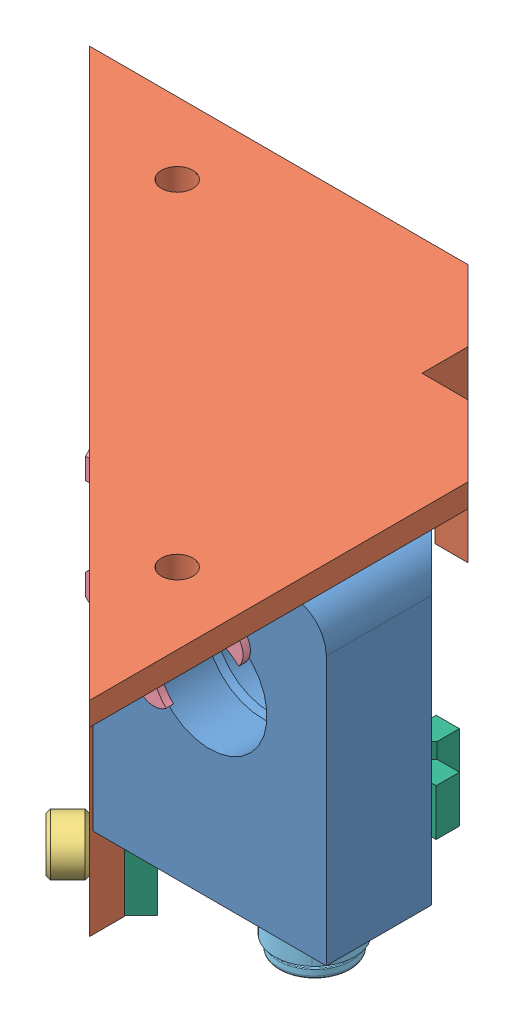
SolidWorks assembly Subtractive Manifold with Cage, configuration Default. Lengths in mm.
Overall size (77.15 60.92 77.15).
8 component instances, 7 part files, 20 mates.
Components (placement in the parent):
- Subtractive Manifold_V2-1: Subtractive Manifold_V2 [Default] at (-2.0967 -24.7998 2.4346) size (44.45 41.27 44.45)
- Manifold Cage Lower-1: Manifold Cage Lower [Default] at (-27.4967 19.6502 27.8346) x (0 0 -1) z (-1 0 0) size (77.15 60.32 77.15)
- Generic_8-32-1: Generic_8-32 [91251A194] at (-18.3833 -32.7373 18.7212) x (0.248031 -0.936462 0.248031) z (-0.707107 0 0.707107) size (6.86 6.86 17.41)
- Valve Clip-1: Valve Clip [Default] at (-27.4967 26.9423 25.6017) x (0 -0.707107 0.707107) z (0 -0.707107 -0.707107) size (18.64 1 15.22)
- Valve Clip-3: Valve Clip [Default] at (-25.2638 26.9423 28.8346) x (-0.707107 -0.707107 0) z (0.707107 -0.707107 0) size (18.64 1 15.22)
- grainger-36x026-1: grainger-36x026 [Default] at (1.0783 -20.0967 13.5471) x (0 -1 0) z (-0.74066 0 0.67188) size (18.47 12.77 12.72)
- grainger-36x026-2: grainger-36x026 [Default] at (-13.2092 -20.0967 -0.7404) x (0 -1 0) z (-0.958276 0 -0.285846) size (18.47 12.77 12.72)
- Manifold Cage Upper-1: Manifold Cage Upper [Default] at (-10.9382 -27.9748 11.2761) x (0.707107 0 -0.707107) z (0.707107 0 0.707107) size (32.25 15.88 11.76)
Mates (geometry in assembly coordinates):
- Coincident1: coincident anti-aligned: plane of Subtractive Manifold_V2-1 through (-2.0967 16.4752 2.4346) normal (0 1 0); plane of Manifold Cage Lower-1 through (-27.4967 16.4752 27.8346) normal (0 -1 0)
- Parallel1: parallel: plane of Subtractive Manifold_V2-1 through (-2.0967 16.4752 -5.5029) normal (0.707107 0 -0.707107); plane of Manifold Cage-1 through (-1.9349 13.3002 -5.8351) normal (-0.707107 0 0.707107)
- Parallel2: parallel: plane of Subtractive Manifold_V2-1 through (-2.0967 16.4752 2.4346) normal (1 0 0); plane of Manifold Cage-1 through (-1.9349 13.3002 -0.9022) normal (-1 0 0)
- Coincident5: coincident aligned: line of Subtractive Manifold_V2-1 through (-14.7967 16.4752 27.8346) axis (1 0 0); line of Manifold Cage Lower-1 through (-15.3047 16.4752 27.8346) axis (1 0 0)
- Coincident6: coincident aligned: line of Subtractive Manifold_V2-1 through (-27.4967 16.4752 15.1346) axis (0 0 -1); line of Manifold Cage Lower-1 through (-27.4967 16.4752 15.6426) axis (0 0 -1)
- Coincident7: coincident anti-aligned: plane of Subtractive Manifold_V2-1 through (-27.4967 16.4752 -16.6154) normal (-1 0 0); plane of Valve Clip-1 through (-27.4967 0.6002 -0.7404) normal (1 0 0)
- Concentric3: concentric aligned: circle of Subtractive Manifold_V2-1; cylinder of Valve Clip-1 through (-28.4967 8.5926 7.252) axis (-1 0 0) radius 2.1526
- Concentric4: concentric anti-aligned: circle of Subtractive Manifold_V2-1; circle of Valve Clip-1
- Coincident8: coincident anti-aligned: plane of Subtractive Manifold_V2-1 through (16.9533 16.4752 27.8346) normal (0 0 1); plane of Valve Clip-3 through (1.0783 0.6002 27.8346) normal (0 0 -1)
- Concentric5: concentric anti-aligned: circle of Subtractive Manifold_V2-1; circle of Valve Clip-3
- Concentric6: concentric anti-aligned: circle of Subtractive Manifold_V2-1; circle of Valve Clip-3
- Coincident9: coincident anti-aligned: plane of Manifold Cage Lower-1 through (-21.4007 -24.7998 21.7386) normal (-0.707107 0 0.707107); circle of Generic_8-32-1
- Concentric7: concentric anti-aligned: circle of Manifold Cage-1; circle of Generic_8-32-1
- Concentric8: concentric aligned: circle of Subtractive Manifold_V2-1; circle of grainger-36x026-1
- Distance1: distance = 2 mm anti-aligned: plane of Subtractive Manifold_V2-1 through (-2.0967 -24.7998 2.4346) normal (0 -1 0); plane of grainger-36x026-1 through (1.0783 -26.7998 13.5471) normal (0 1 0)
- Distance2: distance = 2 mm anti-aligned: plane of grainger-36x026-2 through (-13.2092 -26.7998 -0.7404) normal (0 1 0); plane of Subtractive Manifold_V2-1 through (-2.0967 -24.7998 2.4346) normal (0 -1 0)
- Concentric9: concentric anti-aligned: circle of Subtractive Manifold_V2-1; circle of grainger-36x026-2
- Coincident13: coincident anti-aligned: plane of Subtractive Manifold_V2-1 through (-2.0967 -24.7998 2.4346) normal (0 -1 0); plane of Manifold Cage Upper-1 through (-10.9382 -24.7998 11.2761) normal (0 1 0)
- Coincident14: coincident anti-aligned: plane of Manifold Cage Lower-1 through (-15.3047 -37.4998 23.0721) normal (0.707107 0 -0.707107); plane of Manifold Cage Upper-1 through (-16.7599 -24.7998 21.6169) normal (-0.707107 0 0.707107)
- Concentric10: concentric aligned: circle of Manifold Cage Lower-1; circle of Manifold Cage Upper-1
